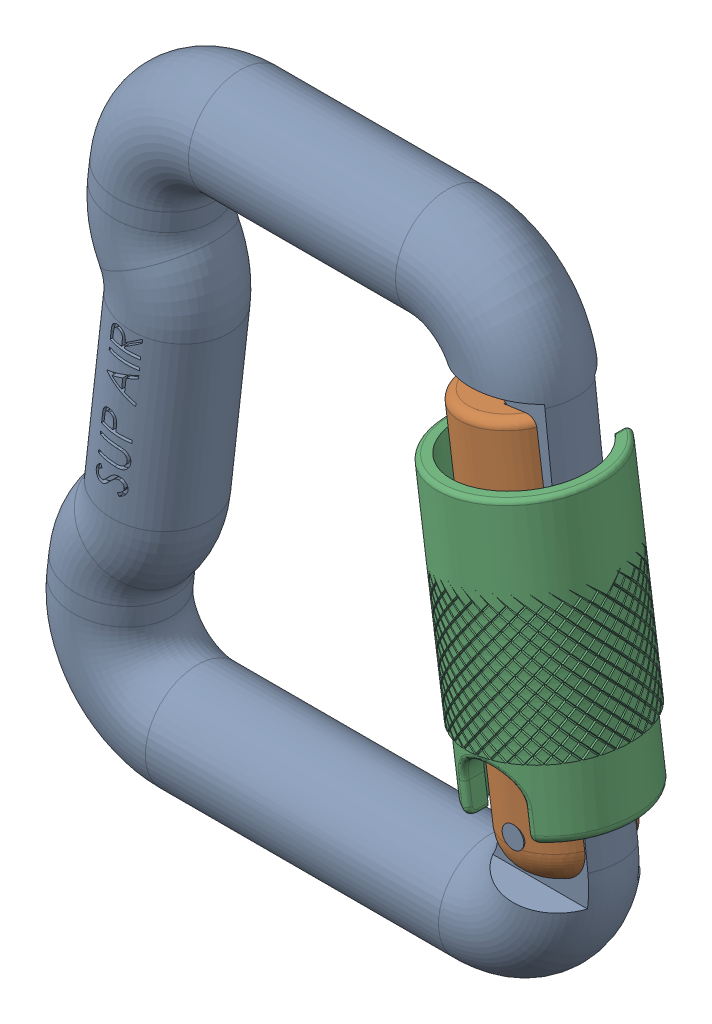
SolidWorks assembly CARABINER SUP AIR, configuration Default. Lengths in mm.
Overall size (66.23 74 18.01).
3 component instances, 3 part files, 4 mates.
Components (placement in the parent):
- CARABINER_MAIN-1: CARABINER_MAIN [Default] at origin size (63.85 74 12.79)
- CARABINER_ARM-1: CARABINER_ARM [Default] at (26.2233 -22.952 0) x (0.990404 0.138202 0) z (0 0 1) size (12 45.37 12.12)
- CARABINER_LOCK-1: CARABINER_LOCK [Default] at (25.3718 -16.8504 0) x (0.990404 0.138202 0) z (0 0 1) size (18.01 33.07 18.01)
Mates (geometry in assembly coordinates):
- Coincident1: coincident aligned: plane of CARABINER_ARM-1 through (25.9507 -22.4648 0) normal (0 0 1); plane of assembly through (0 0 0) normal (0 0 1)
- Concentric2: concentric aligned: cylinder of CARABINER_ARM-1 through (19.7316 22.1034 0) axis (0.138202 -0.990404 0) radius 6; cylinder of CARABINER_LOCK-1 through (20.6105 15.8049 0) axis (0.138202 -0.990404 0) radius 9
- Coincident2: coincident aligned: plane of CARABINER_LOCK-1 through (25.1712 -16.8784 0) normal (0 0 1); plane of assembly through (0 0 0) normal (0 0 1)
- Concentric4: concentric anti-aligned: cylinder of CARABINER_MAIN-1 through (25.5323 -18 6) axis (0 0 -1) radius 1.25; cylinder of CARABINER_ARM-1 through (25.5323 -18 -6) axis (0 0 1) radius 1.25
